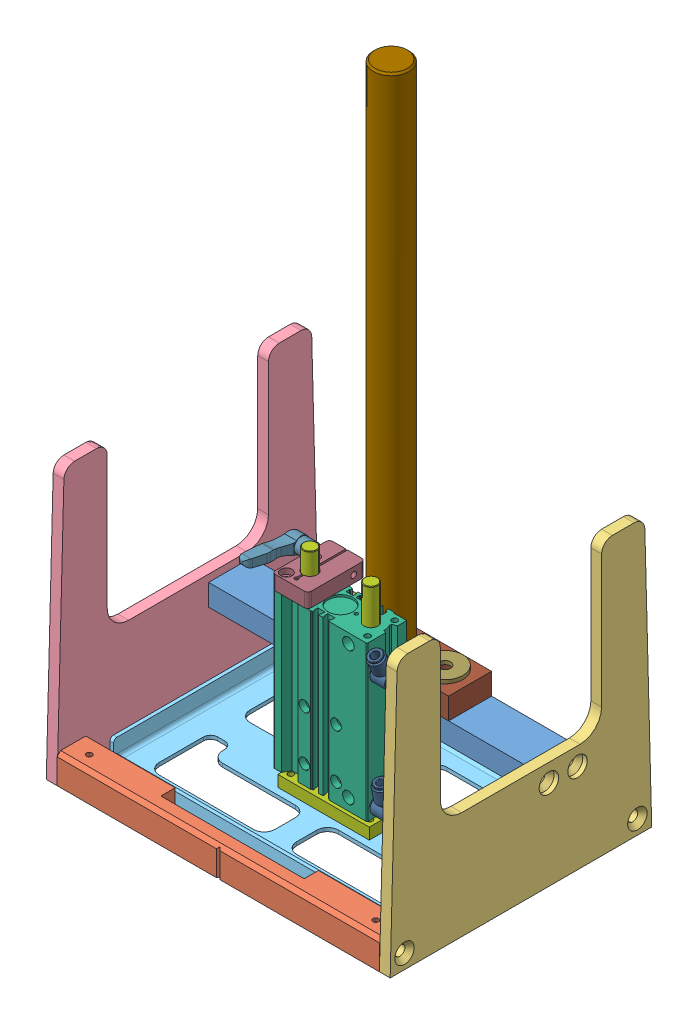
SolidWorks assembly MANDREL ASSEMBLY, configuration Default. Lengths in mm.
Overall size (304.8 552.45 231.84).
18 component instances, 14 part files, 39 mates.
Components (placement in the parent):
- MANDREL CENTER MOUNT BAR-1: MANDREL CENTER MOUNT BAR [Default] at origin size (285.75 19.05 38.1)
- MANDREL SPREADER-1: MANDREL SPREADER [Default] at (0 -66.675 140.6779) size (285.75 25.4 25.4)
- MANDREL SPREADER-2: MANDREL SPREADER [Default] at (0 -66.675 -65.7606) x (-1 0 0) z (0 0 -1) size (285.75 25.4 25.4)
- MANDREL SIDE PLATE 2-1: MANDREL SIDE PLATE 2 [5086-21-107] at (142.875 -31.75 37.4587) x (0 1 0) z (1 0 0) size (241.3 231.84 9.53)
- MANDREL SIDE PLATE-1: MANDREL SIDE PLATE [5086-21-107] at (-142.875 -31.75 37.4587) x (0 1 0) z (-1 0 0) size (241.3 231.84 9.53)
- PUSHER PLATE-1: PUSHER PLATE [Default] at (0 -76.2 37.4587) x (-1 0 0) z (0 0 -1) size (275.34 19.05 173.84)
- CYLINDER ASSEMBLY-1: CYLINDER ASSEMBLY [MGPM20N-100] at (0 8.3 44.9875) x (1 0 0) z (0 -1 0) size (83 36 184.5)
  - R&D5321-31 SMC MGPM20N-100_MGPTube-1: R&D5321-31 SMC MGPM20N-100_MGPTube [20M] at origin size (83 36 137)
  - R&D5321-31 SMC MGPM20N-100_MGPRod-1: R&D5321-31 SMC MGPM20N-100_MGPRod [20M] at (0 0 -52.5) size (81 30 184.5)
- CYLINDER PUSHER MOUNT-1: CYLINDER PUSHER MOUNT [Default] at (0 -9.525 26.9875) x (0 0 -1) z (1 0 0) size (50.8 50.8 76.2)
- MANDREL STEM-1: MANDREL STEM [Default] at (0 244.475 0) x (1 0 0) z (0 -1 0) size (31.75 31.75 457.2)
- ELBOW-1: ELBOW [Default] at (51.0375 52.3 55.4875) x (0 -0.90635 -0.422527) z (0 -0.422527 0.90635) size (31 36.1 14.2)
- ELBOW-2: ELBOW [Default] at (51.0375 -49.7 55.4875) x (0 -0.979591 -0.201) z (0 -0.201 0.979591) size (31 36.1 14.2)
- MANDREL MNT-1: MANDREL MNT [Default] at (0 19.05 0) x (0 0 -1) z (-1 0 0) size (38.1 19.05 139.7)
- WASHER ECCENT-1: WASHER ECCENT [Default] at (47.625 30.1625 0) x (-0.379258 0 0.925291) z (0.925291 0 0.379258) size (31.75 3.17 31.75)
- WASHER ECCENT-2: WASHER ECCENT [Default] at (-47.625 30.1625 0) x (-0.379258 0 0.925291) z (0.925291 0 0.379258) size (31.75 3.17 31.75)
- EJECT CYLINDER CLAMP PLATE-1: EJECT CYLINDER CLAMP PLATE [Default] at (-26.475 83.15 37.9375) x (-1 0 0) z (0 0 -1) size (31.75 12.7 50.8)
- ORANGE HANDLE-1: ORANGE HANDLE [Default] at (-42.35 83.15 22.7625) x (0 0 1) z (0 -1 0) size (46.51 30.96 14.49)
Mates (geometry in assembly coordinates):
- Coincident1: coincident: plane of MANDREL CENTER MOUNT BAR-1 through (142.875 9.525 19.05) normal (1 0 0); plane of MANDREL SIDE PLATE 2-1 through (142.875 -79.375 -78.4606) normal (-1 0 0)
- Concentric1: concentric: cylinder of MANDREL CENTER MOUNT BAR-1 through (142.875 0 12.7) axis (1 0 0) radius 3.4; cylinder of MANDREL SIDE PLATE 2-1 through (152.4 0 12.7) axis (1 0 0) radius 4.5
- Concentric2: concentric: cylinder of MANDREL CENTER MOUNT BAR-1 through (142.875 0 -12.7) axis (1 0 0) radius 3.4; cylinder of MANDREL SIDE PLATE 2-1 through (152.4 0 -12.7) axis (1 0 0) radius 4.5
- Coincident2: coincident: plane of MANDREL SIDE PLATE 2-1 through (142.875 -79.375 -78.4606) normal (-1 0 0); plane of MANDREL SPREADER-1 through (142.875 -79.375 153.3779) normal (1 0 0)
- Coincident22: coincident: plane of MANDREL SPREADER-2 through (142.875 -79.375 -78.4606) normal (1 0 0); plane of MANDREL SIDE PLATE 2-1 through (142.875 -79.375 -78.4606) normal (-1 0 0)
- Coincident23: coincident: plane of MANDREL SIDE PLATE 2-1 through (152.4 -79.375 153.3779) normal (0 -1 0); plane of MANDREL SPREADER-2 through (-142.875 -79.375 -78.4606) normal (0 -1 0)
- Coincident24: coincident: plane of MANDREL SPREADER-1 through (-142.875 -79.375 153.3779) normal (-1 0 0); plane of MANDREL SIDE PLATE-1 through (-142.875 -79.375 -78.4606) normal (1 0 0)
- Concentric29: concentric: cylinder of MANDREL SPREADER-1 through (-142.875 -66.675 140.6779) axis (-1 0 0) radius 3.4; cylinder of MANDREL SIDE PLATE-1 through (-152.4 -66.675 140.6779) axis (-1 0 0) radius 4.5
- Concentric30: concentric: cylinder of MANDREL SPREADER-2 through (-142.875 -66.675 -65.7606) axis (-1 0 0) radius 3.4; cylinder of MANDREL SIDE PLATE-1 through (-152.4 -66.675 -65.7606) axis (-1 0 0) radius 4.5
- Concentric60: concentric: cylinder of MANDREL SPREADER-1 through (142.875 -66.675 140.6779) axis (1 0 0) radius 3.4; cylinder of MANDREL SIDE PLATE 2-1 through (152.4 -66.675 140.6779) axis (1 0 0) radius 4.5
- Coincident72: coincident: plane of MANDREL CENTER MOUNT BAR-1 through (142.875 -9.525 19.05) normal (0 -1 0); plane of CYLINDER PUSHER MOUNT-1 through (38.1 -9.525 26.9875) normal (0 1 0)
- Coincident75: coincident: plane of PUSHER PLATE-1 through (131.318 -76.2 -43.1101) normal (0 1 0); plane of CYLINDER ASSEMBLY-1/R&D5321-31 SMC MGPM20N-100_MGPRod-1 through (-40.5 -76.2 29.9875) normal (0 -1 0)
- Coincident77: coincident: plane of MANDREL SPREADER-2 through (-142.875 -79.375 -78.4606) normal (0 -1 0); plane of PUSHER PLATE-1 through (131.318 -79.375 -43.1101) normal (0 -1 0)
- Coincident78: coincident: plane of CYLINDER ASSEMBLY-1/R&D5321-31 SMC MGPM20N-100_MGPTube-1 through (0 8.3 44.9875) normal (1 0 0); plane of CYLINDER PUSHER MOUNT-1 through (0 -9.525 26.9875) normal (1 0 0)
- Coincident79: coincident: plane of CYLINDER ASSEMBLY-1/R&D5321-31 SMC MGPM20N-100_MGPTube-1 through (-41.5 -150.671 26.9875) normal (0 0 -1); plane of CYLINDER PUSHER MOUNT-1 through (38.1 -9.525 26.9875) normal (0 0 1)
- Coincident80: coincident: plane of ELBOW-1 through (36.7375 54.6304 61.8882) normal (-1 0 0); plane of ELBOW-2 through (36.7375 -45.9498 61.1739) normal (-1 0 0)
- Distance1: distance = 4.7625 mm: plane of CYLINDER ASSEMBLY-1/R&D5321-31 SMC MGPM20N-100_MGPTube-1 through (41.5 -150.671 62.9875) normal (1 0 0); plane of ELBOW-2 through (36.7375 -45.9498 61.1739) normal (-1 0 0)
- Concentric65: concentric: circle of CYLINDER ASSEMBLY-1/R&D5321-31 SMC MGPM20N-100_MGPTube-1; cylinder of ELBOW-1 through (56.7375 52.3 55.4875) axis (-1 0 0) radius 7.1
- Concentric66: concentric: circle of CYLINDER ASSEMBLY-1/R&D5321-31 SMC MGPM20N-100_MGPTube-1; circle of ELBOW-2
- Coincident87: coincident: plane of MANDREL CENTER MOUNT BAR-1 through (0 0 0) normal (0 0 1); plane of MANDREL STEM-1 through (0 244.475 0) normal (0 0 1)
- Distance2: distance = 6.35 mm: plane of MANDREL CENTER MOUNT BAR-1 through (142.875 9.525 19.05) normal (0 1 0); plane of MANDREL STEM-1 through (0 15.875 0) normal (0 -1 0)
- Coincident89: coincident: plane of MANDREL CENTER MOUNT BAR-1 through (0 0 0) normal (1 0 0); plane of MANDREL STEM-1 through (0 244.475 0) normal (1 0 0)
- Coincident90: coincident: plane of MANDREL CENTER MOUNT BAR-1 through (142.875 9.525 19.05) normal (0 1 0); plane of MANDREL MNT-1 through (-69.85 9.525 19.05) normal (0 -1 0)
- Coincident91: coincident: plane of MANDREL CENTER MOUNT BAR-1 through (0 0 0) normal (0 0 1); plane of MANDREL MNT-1 through (0 19.05 0) normal (0 0 -1)
- Coincident92: coincident: plane of MANDREL CENTER MOUNT BAR-1 through (0 0 0) normal (1 0 0); plane of MANDREL MNT-1 through (0 19.05 0) normal (-1 0 0)
- Coincident93: coincident: plane of WASHER ECCENT-1 through (47.625 28.575 0) normal (0 -1 0); plane of WASHER ECCENT-2 through (-47.625 28.575 0) normal (0 -1 0)
- Coincident94: coincident: plane of MANDREL MNT-1 through (-69.85 28.575 19.05) normal (0 1 0); plane of WASHER ECCENT-1 through (47.625 28.575 0) normal (0 -1 0)
- Concentric67: concentric: cylinder of MANDREL MNT-1 through (47.625 28.576 0) axis (0 -1 0) radius 9.525; cylinder of WASHER ECCENT-1 through (47.625 28.575 0) axis (0 1 0) radius 4.9609
- Concentric68: concentric: cylinder of MANDREL MNT-1 through (-47.625 28.576 0) axis (0 -1 0) radius 9.525; cylinder of WASHER ECCENT-2 through (-47.625 28.575 0) axis (0 1 0) radius 4.9609
- Concentric69: concentric: cylinder of MANDREL CENTER MOUNT BAR-1 through (-19.05 -9.525 -12.7) axis (0 -1 0) radius 2.1; cylinder of CYLINDER PUSHER MOUNT-1 through (-19.05 -9.525 -12.7) axis (0 1 0) radius 2.7781
- Concentric70: concentric: cylinder of MANDREL CENTER MOUNT BAR-1 through (19.05 -9.525 12.7) axis (0 -1 0) radius 2.1; cylinder of CYLINDER PUSHER MOUNT-1 through (19.05 -9.525 12.7) axis (0 1 0) radius 2.7781
- Width1: width: plane of PUSHER PLATE-1 through (124.968 -60.325 -49.4601) normal (0 0 -1); plane of PUSHER PLATE-1 through (0 -76.2 124.3774) normal (0 0 1); plane of MANDREL SPREADER-2 through (-142.875 -53.975 -53.0606) normal (0 0 1); plane of MANDREL SPREADER-1 through (142.875 -53.975 127.9779) normal (0 0 -1)
- Width2: width: plane of PUSHER PLATE-1 through (-137.668 -76.2 111.6774) normal (-1 0 0); plane of PUSHER PLATE-1 through (137.668 -76.2 -36.7601) normal (1 0 0); plane of MANDREL SIDE PLATE 2-1 through (152.4 -79.375 -78.4606) normal (1 0 0); plane of MANDREL SIDE PLATE-1 through (-152.4 -79.375 -78.4606) normal (-1 0 0)
- Concentric71: concentric: cylinder of CYLINDER ASSEMBLY-1/R&D5321-31 SMC MGPM20N-100_MGPRod-1 through (-27 125.2706 44.9875) axis (0 -1 0) radius 6; cylinder of EJECT CYLINDER CLAMP PLATE-1 through (-27 76.799 44.9875) axis (0 1 0) radius 6
- Concentric72: concentric: cylinder of CYLINDER ASSEMBLY-1/R&D5321-31 SMC MGPM20N-100_MGPTube-1 through (-36 63.8 56.9875) axis (0 1 0) radius 2.5; cylinder of EJECT CYLINDER CLAMP PLATE-1 through (-36 89.5 56.9875) axis (0 1 0) radius 5
- Coincident95: coincident: plane of CYLINDER ASSEMBLY-1/R&D5321-31 SMC MGPM20N-100_MGPTube-1 through (0 76.8 44.9875) normal (0 1 0); plane of EJECT CYLINDER CLAMP PLATE-1 through (-10.6 76.8 12.5375) normal (0 -1 0)
- Coincident96: coincident: plane of EJECT CYLINDER CLAMP PLATE-1 through (-42.35 76.8 12.5375) normal (-1 0 0); plane of ORANGE HANDLE-1 through (-42.35 83.15 27.4625) normal (1 0 0)
- Concentric73: concentric: cylinder of EJECT CYLINDER CLAMP PLATE-1 through (-42.35 83.15 22.7625) axis (-1 0 0) radius 3.3735; cylinder of ORANGE HANDLE-1 through (-42.35 83.15 22.7625) axis (-1 0 0) radius 5
- Parallel1: parallel: plane of EJECT CYLINDER CLAMP PLATE-1 through (-10.6 89.5 12.5375) normal (0 1 0); plane of ORANGE HANDLE-1 through (-42.35 83.15 22.7625) normal (0 -1 0)
